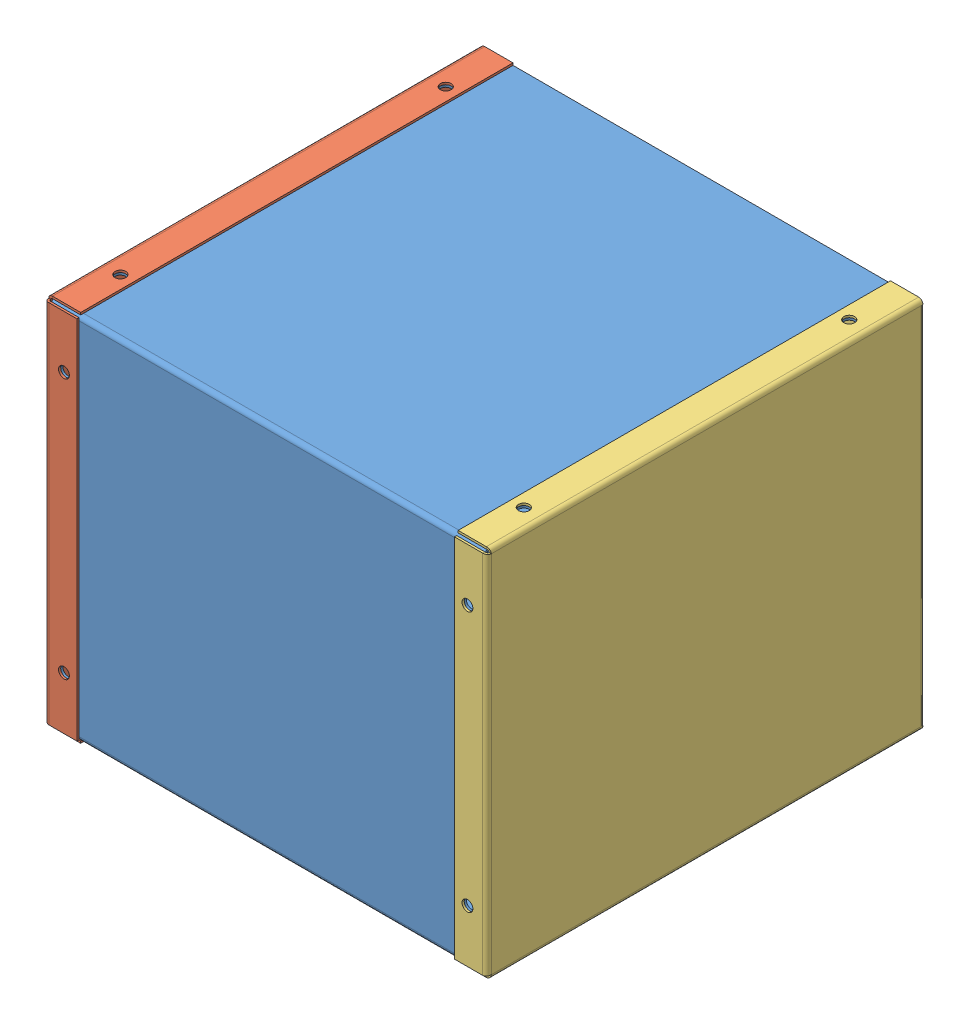
SolidWorks assembly Cabin, configuration Default. Lengths in mm.
Overall size (204 172 202).
3 component instances, 3 part files, 6 mates.
Components (placement in the parent):
- Back-1: Back [Default] at (39.6811 72.4664 193.6476) size (200 170 200)
- Side_R-1: Side_R [Default] at (-62.3189 72.4664 93.6476) x (0 0 1) z (-1 0 0) size (202 172 40)
- Side_L-1: Side_L [Default] at (140.6811 72.4664 93.6476) x (0 0 1) z (-1 0 0) size (202 172 40)
Mates (geometry in assembly coordinates):
- Concentric2: concentric aligned: cylinder of Back-1 through (-53.3189 12.4664 183.6476) axis (0 0 1) radius 2.5; cylinder of Side_R-1 through (-53.3189 12.4664 14.6476) axis (0 0 1) radius 2.5
- Concentric3: concentric aligned: cylinder of Back-1 through (-53.3189 132.4664 183.6476) axis (0 0 1) radius 2.5; cylinder of Side_R-1 through (-53.3189 132.4664 14.6476) axis (0 0 1) radius 2.5
- Coincident4: coincident anti-aligned: plane of Back-1 through (39.6811 72.4664 193.6476) normal (0 0 1); plane of Side_R-1 through (-62.3189 72.4664 193.6476) normal (0 0 -1)
- Concentric4: concentric aligned: cylinder of Back-1 through (132.6811 132.4664 183.6476) axis (0 0 1) radius 2.5; cylinder of Side_L-1 through (132.6811 132.4664 14.6476) axis (0 0 1) radius 2.5
- Concentric5: concentric aligned: cylinder of Back-1 through (132.6811 12.4664 183.6476) axis (0 0 1) radius 2.5; cylinder of Side_L-1 through (132.6811 12.4664 14.6476) axis (0 0 1) radius 2.5
- Concentric7: concentric aligned: cylinder of Back-1 through (132.6811 -22.5336 168.6476) axis (0 1 0) radius 2.5; cylinder of Side_L-1 through (132.6811 -21.5336 168.6476) axis (0 1 0) radius 2.5
